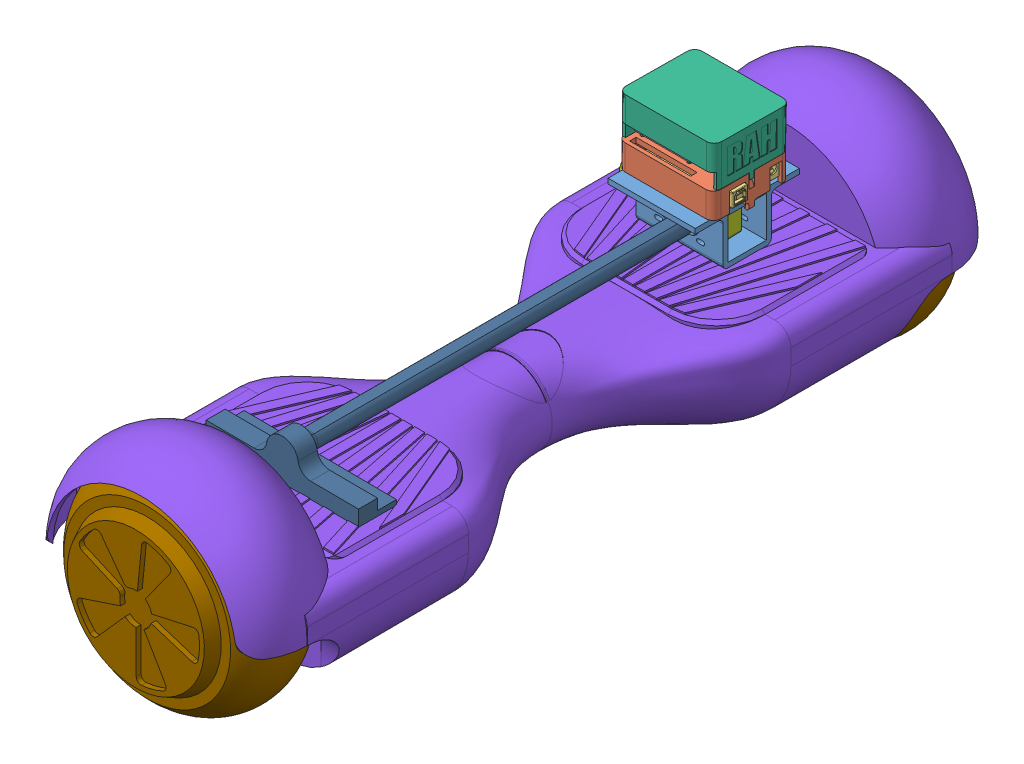
SolidWorks assembly enclosure2, configuration Default. Lengths in mm.
Overall size (229.8 236.3 592.69).
12 component instances, 10 part files, 8 mates.
Components (placement in the parent):
- Mountenclosed-1: Mountenclosed [Default] at (-26.0982 -8.0654 15) size (68.6 40 82)
- arduinoenclosure-1: arduinoenclosure [Default] at (8.238 47.979 0) x (1 -0.000185 0) z (0 0 -1) size (75.6 26 60.4)
- arduino uno-1: arduino uno [Default] at (42.032 32.1988 -26.67) x (0 0 -1) z (1 0 0) size (53.34 15.25 74.93)
- L298N-1: L298N [Predeterminado] at (-3.1427 52.9742 -0.1885) size (43 30 43)
- Microphone Module-1: Microphone Module [Default] at (63.9466 36.5842 -13.1792) x (-0.008727 0 0.999962) z (-0.999962 0 -0.008727) size (42.03 14.59 15)
- motorconenclosure-1: motorconenclosure [Default] at (8.1676 80.0578 -0.5876) x (1 0 0) z (0 -0.008727 -0.999962) size (75.6 37 60.4)
- JGY-370-1: JGY-370 [-00] at (13.4138 7.3272 11.1595) size (80.3 31.6 41.23)
- Assem1-2: Assem1 [Default] at (221.3455 -122.3588 -86.5346) x (0 0 1) z (-1 0 0) size (592.69 229.8 229.8)
  - Part2-1: Part2 [Default] at (-11.955 68.58 208.6829) size (584.2 143.52 185.44)
  - Wheel2-1: Wheel2 [Default] at (-12.1887 81.28 208.6829) x (-1 0 0) z (0 0.727203 -0.686422) size (75.33 162.56 162.56)
  - Wheel2-4: Wheel2 [Default] at (496.2788 81.28 208.6829) x (1 0 0) z (0 -0.781011 0.624518) size (75.33 162.56 162.56)
- Extendo-1: Extendo [Default] at (13.4138 7.3272 322.1526) x (-0.999981 0.006122 0) z (0 0 -1) size (120 32 315)
Mates (geometry in assembly coordinates):
- Coincident5: coincident: point of Mountenclosed-1
- Parallel1: parallel aligned: plane of Mountenclosed-1 through (-26.0982 -8.0654 41) normal (0 0 1)
- Parallel2: parallel aligned: plane of assembly through (0 0 0) normal (0 0 1); plane of arduinoenclosure-1 through (46.0343 27.972 30.2) normal (0 0 1)
- Parallel3: parallel anti-aligned: plane of arduino uno-1 through (42.032 30.5488 -26.67) normal (0 0 -1)
- Coincident9: coincident: unknown of arduino uno-1
- Parallel4: parallel anti-aligned: plane of Mountenclosed-1 through (42.5018 -8.0654 19) normal (0 0 1); plane of Extendo-1 through (13.4138 7.3272 22.1526) normal (0 0 -1)
- Concentric2: concentric anti-aligned: cylinder of JGY-370-1 through (13.4138 7.3272 26.8595) axis (0 0 -1) radius 3; cylinder of Extendo-1 through (13.4138 7.3272 22.1526) axis (0 0 1) radius 3
- Parallel6: parallel anti-aligned: plane of Assem1-2/Part2-1 through (12.6626 51.6322 371.4104) normal (0 0 -1); plane of Extendo-1 through (13.4138 7.3272 337.1526) normal (0 0 1)
